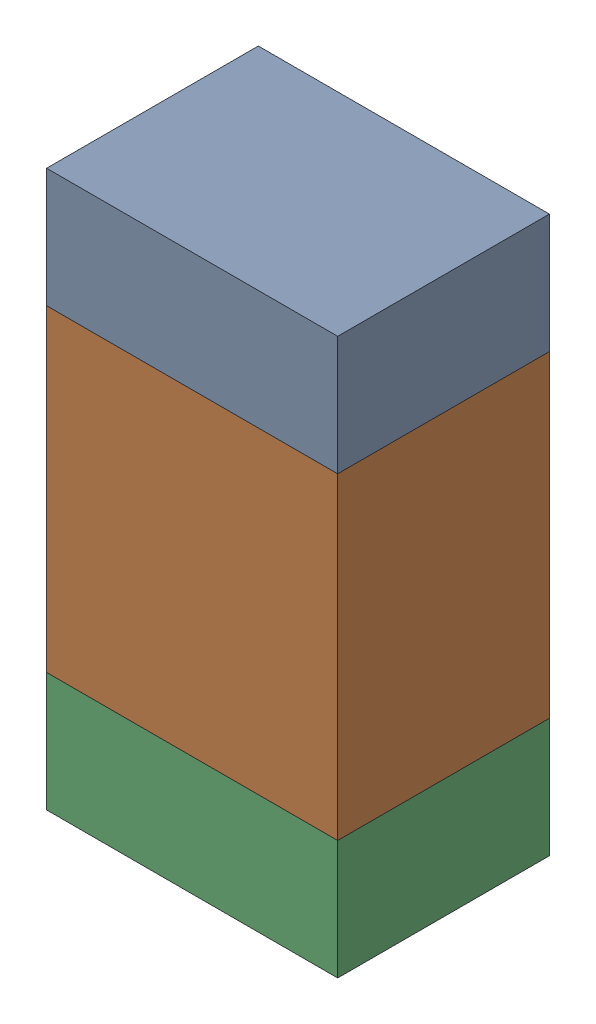
SolidWorks assembly R104_1PCB, configuration Default. Lengths in mm.
Overall size (0.55 1.05 0.4).
6 component instances, 2 part files, 0 mates.
Components (placement in the parent):
- 846483288-1: 846483288 [Default] at (117.6001 114.0124 0) size (0.55 0.22 0.4)
  - Extruded_12-1: Extruded_12 [Default] at origin size (0.55 0.22 0.4)
- 846483424-1: 846483424 [Default] at (117.6001 113.5999 0) size (0.55 0.6 0.4)
  - Extruded_13-1: Extruded_13 [Default] at origin size (0.55 0.6 0.4)
- 846483288-2: 846483288 [Default] at (117.6001 113.1874 0) size (0.55 0.22 0.4)
  - Extruded_12-1: Extruded_12 [Default] at origin size (0.55 0.22 0.4)
